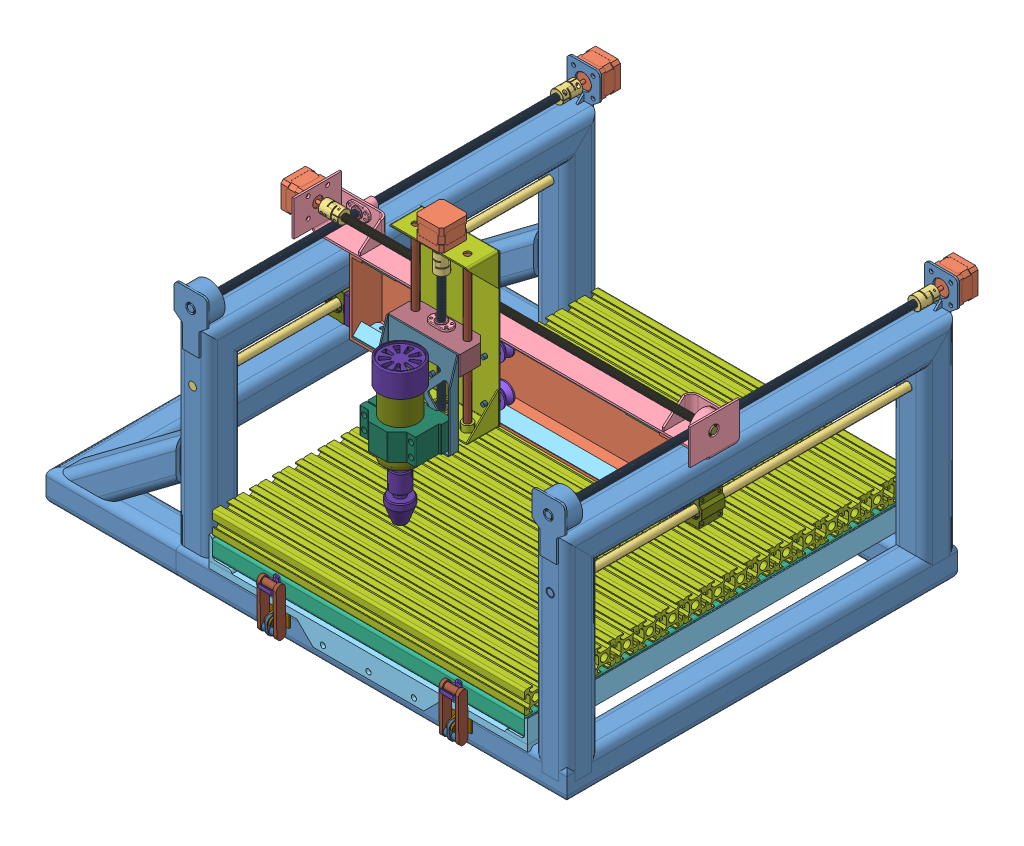
SolidWorks assembly CNC 1.0, configuration Predeterminado. Lengths in mm.
Overall size (806.85 513.22 661.72).
96 component instances, 36 part files, 133 mates.
Components (placement in the parent):
- bastidor-1: bastidor [Predeterminado<Como mecanizada>] at (-1053.2463 119.027 1114.0409) x (-1 0 0) z (0 1 0) size (800.8 613.8 400.8)
- Puente-1: Puente [Predeterminado] at (-1053.2463 333.127 1150.1798) x (0 0 1) z (-1 0 0) size (50 115 496)
- riel eje x-1: riel eje x [Predeterminado] at (-1328.2463 364.427 808.6409) x (0.953714 -0.300715 0) z (0 0 1) size (12 12 605.8)
- riel eje x-2: riel eje x [Predeterminado] at (-778.2463 364.427 805.6409) x (0.828 -0.560727 0) z (0 0 1) size (12 12 605.8)
- soporte superior puente-2: soporte superior puente [Predeterminado] at (-1053.2463 447.127 1177.1798) x (1 0 0) z (0 1 0) size (612.02 76.01 60.01)
- Riel inferior eje Y-2: Riel inferior eje Y [Predeterminado<Como mecanizada>] at (-1053.2463 352.1478 1186.0376) x (1 0 0) z (0 -0.707107 -0.707107) size (488 29.73 29.73)
- Riel superior eje Y-1: Riel superior eje Y [Predeterminado<Como mecanizada>] at (-1053.2463 433.1062 1186.0376) x (-1 0 0) z (0 0.707107 -0.707107) size (488 29.73 29.73)
- eje z-1: eje z [Predeterminado] at (-1121.4295 412.2919 938.479) x (0 0 -1) z (1 0 0) size (79 235.47 120)
  - base eje Z-1: base eje Z [Predeterminado] at (-267.5586 43.8217 -2.3467) x (0 0 -1) z (1 0 0) size (120 235.47 50)
  - Conjunto rodillo eje Y-1: Conjunto rodillo eje Y [Predeterminado] at (-239.2795 9.9817 -72.3048) x (1 0 0) z (0 0.031575 0.999501) size (36 30.93 30.93)
    - rodillo eje Y-1: rodillo eje Y [Predeterminado] at (-16.2791 0.8532 30) size (16 30 30)
    - Rodamiento 9x17-1: Rodamiento 9x17 [Predeterminado] at (-15.2791 0.8532 30) x (1 0 0) z (0 0.05029 0.998735) size (4 17 17)
    - Rodamiento 9x17-2: Rodamiento 9x17 [Predeterminado] at (-5.2791 0.8532 30) x (1 0 0) z (0 -0.414161 0.910204) size (4 17 17)
    - Eje de Rodillo en Y-2: Eje de Rodillo en Y [Predeterminado] at (-15.2791 0.8532 30) x (-1 0 0) z (0 0.999501 0.031575) size (36 30 30)
  - Conjunto rodillo eje Y-2: Conjunto rodillo eje Y [Predeterminado] at (-239.2795 9.9817 7.6952) x (1 0 0) z (0 0.031575 0.999501) size (36 30.93 30.93)
    - rodillo eje Y-1: rodillo eje Y [Predeterminado] at (-16.2791 0.8532 30) size (16 30 30)
    - Rodamiento 9x17-1: Rodamiento 9x17 [Predeterminado] at (-15.2791 0.8532 30) x (1 0 0) z (0 0.05029 0.998735) size (4 17 17)
    - Rodamiento 9x17-2: Rodamiento 9x17 [Predeterminado] at (-5.2791 0.8532 30) x (1 0 0) z (0 -0.414161 0.910204) size (4 17 17)
    - Eje de Rodillo en Y-2: Eje de Rodillo en Y [Predeterminado] at (-15.2791 0.8532 30) x (-1 0 0) z (0 0.999501 0.031575) size (36 30 30)
  - Conjunto rodillo eje Y-3: Conjunto rodillo eje Y [Predeterminado] at (-239.2795 -52.9783 7.6952) x (1 0 0) z (0 0.031575 0.999501) size (36 30.93 30.93)
    - rodillo eje Y-1: rodillo eje Y [Predeterminado] at (-16.2791 0.8532 30) size (16 30 30)
    - Rodamiento 9x17-1: Rodamiento 9x17 [Predeterminado] at (-15.2791 0.8532 30) x (1 0 0) z (0 0.05029 0.998735) size (4 17 17)
    - Rodamiento 9x17-2: Rodamiento 9x17 [Predeterminado] at (-5.2791 0.8532 30) x (1 0 0) z (0 -0.414161 0.910204) size (4 17 17)
    - Eje de Rodillo en Y-2: Eje de Rodillo en Y [Predeterminado] at (-15.2791 0.8532 30) x (-1 0 0) z (0 0.999501 0.031575) size (36 30 30)
  - Conjunto rodillo eje Y-4: Conjunto rodillo eje Y [Predeterminado] at (-239.2795 -52.9783 -72.3048) x (1 0 0) z (0 0.031575 0.999501) size (36 30.93 30.93)
    - rodillo eje Y-1: rodillo eje Y [Predeterminado] at (-16.2791 0.8532 30) size (16 30 30)
    - Rodamiento 9x17-1: Rodamiento 9x17 [Predeterminado] at (-15.2791 0.8532 30) x (1 0 0) z (0 0.05029 0.998735) size (4 17 17)
    - Rodamiento 9x17-2: Rodamiento 9x17 [Predeterminado] at (-5.2791 0.8532 30) x (1 0 0) z (0 -0.414161 0.910204) size (4 17 17)
    - Eje de Rodillo en Y-2: Eje de Rodillo en Y [Predeterminado] at (-15.2791 0.8532 30) x (-1 0 0) z (0 0.999501 0.031575) size (36 30 30)
- Guia eje z-1: Guia eje z [Predeterminado] at (-1163.7761 340.377 1236.0376) x (0 1 0) z (-0.194259 0 0.98095) size (231 10 10)
- Guia eje z-2: Guia eje z [Predeterminado] at (-1083.7761 340.377 1236.0376) x (0 1 0) z (-0.034634 0 0.9994) size (231 10 10)
- rodamiento skf 10X25-1: rodamiento skf 10X25 [Predeterminado] at (-1123.7761 344.377 1236.0376) x (1 0 0) z (0 -1 0) size (25 25 8)
- Bancada eje z-1: Bancada eje z [Predeterminado] at (-1123.7761 460.3554 1242.0376) x (1 0 0) z (0 -1 0) size (110 42 30)
- soporte spindle-1: soporte spindle [Predeterminado] at (-1123.7761 395.3554 1265.0376) size (110.01 130.01 15.01)
- soporte de fijacion spindle-1: soporte de fijacion spindle [Predeterminado] at (-1123.7761 372.3554 1299.5376) x (1 0 0) z (0 -1 0) size (91 69 40)
- case spindle-1: case spindle [Predeterminado] at (-1123.7761 368.3554 1299.5376) x (-0.921943 0 0.387327) z (0 -1 0) size (52 52 120)
- eje spindle-1: eje spindle [Predeterminado] at (-1038.5141 306.3381 1358.5305) x (-0.822349 0 -0.568984) z (0.568984 0 -0.822349) size (62 219.98 62)
- Rodamiento 10x30-1: Rodamiento 10x30 [Predeterminado] at (-778.2463 469.427 1405.4409) size (30 30 9)
- Rodamiento 10x30-2: Rodamiento 10x30 [Predeterminado] at (-1328.2463 469.427 1405.4409) size (30 30 9)
- tornillo de potencia-1: tornillo de potencia [Predeterminado] at (-1328.2463 469.427 850.4409) x (-0.050492 -0.998724 0) z (0 0 1) size (11.55 10 570.26)
- nema 17-2-1: nema 17-2 [Predeterminado] at (-1328.2463 469.427 794.1409) x (0 0 1) z (-1 0 0) size (56.5 42 42)
- CPJC20-RD-5-10-1: CPJC20-RD-5-10 [Default] at (-1328.2463 469.427 824.1409) x (0 0 1) z (0.050492 0.998724 0) size (30 20 20)
- nema 17-2-2: nema 17-2 [Predeterminado] at (-778.2463 469.427 794.1409) x (0 0 1) z (-1 0 0) size (56.5 42 42)
- tornillo de potencia-3: tornillo de potencia [Predeterminado] at (-778.2463 469.427 850.4409) x (-0.996451 -0.084175 0) z (0 0 1) size (11.55 10 570.26)
- CPJC20-RD-5-10-2: CPJC20-RD-5-10 [Default] at (-778.2463 469.427 824.4409) x (0 0 1) z (0.996451 0.084175 0) size (30 20 20)
- soporte ball screw-1: soporte ball screw [Predeterminado] at (-778.2463 469.427 1157.1798) size (35 20 29.83)
- soporte ball screw-2: soporte ball screw [Predeterminado] at (-1328.2463 469.427 1157.1798) x (-1 0 0) z (0 0 1) size (35 20 29.83)
- Base desmontable-1: Base desmontable [Predeterminado<Como mecanizada>] at (-1052.8463 149.427 1119.4409) x (1 0 0) z (0 1 0) size (490 600 70)
- Base-1: Base [Predeterminado] at (-955.1042 369.297 526.9409) size (480 65 595)
  - Marco base-1: Marco base [Predeterminado<Como mecanizada>] at (-97.7421 -184.87 595) x (1 0 0) z (0 -1 0) size (480 595 30)
  - perfil estructural aluminio base-1: perfil estructural aluminio base [Predeterminado] at (-337.7421 -167.37 875) x (0 0 -1) z (1 0 0) size (35 35 480)
  - perfil estructural aluminio base-2: perfil estructural aluminio base [Predeterminado] at (-337.7421 -167.37 840) x (0 0 -1) z (1 0 0) size (35 35 480)
  - perfil estructural aluminio base-3: perfil estructural aluminio base [Predeterminado] at (-337.7421 -167.37 805) x (0 0 -1) z (1 0 0) size (35 35 480)
  - perfil estructural aluminio base-4: perfil estructural aluminio base [Predeterminado] at (-337.7421 -167.37 770) x (0 0 -1) z (1 0 0) size (35 35 480)
  - perfil estructural aluminio base-5: perfil estructural aluminio base [Predeterminado] at (-337.7421 -167.37 735) x (0 0 -1) z (1 0 0) size (35 35 480)
  - perfil estructural aluminio base-6: perfil estructural aluminio base [Predeterminado] at (-337.7421 -167.37 700) x (0 0 -1) z (1 0 0) size (35 35 480)
  - perfil estructural aluminio base-7: perfil estructural aluminio base [Predeterminado] at (-337.7421 -167.37 665) x (0 0 -1) z (1 0 0) size (35 35 480)
  - perfil estructural aluminio base-8: perfil estructural aluminio base [Predeterminado] at (-337.7421 -167.37 630) x (0 0 -1) z (1 0 0) size (35 35 480)
  - perfil estructural aluminio base-9: perfil estructural aluminio base [Predeterminado] at (-337.7421 -167.37 595) x (0 0 -1) z (1 0 0) size (35 35 480)
  - perfil estructural aluminio base-10: perfil estructural aluminio base [Predeterminado] at (-337.7421 -167.37 560) x (0 0 -1) z (1 0 0) size (35 35 480)
  - perfil estructural aluminio base-11: perfil estructural aluminio base [Predeterminado] at (-337.7421 -167.37 525) x (0 0 -1) z (1 0 0) size (35 35 480)
  - perfil estructural aluminio base-12: perfil estructural aluminio base [Predeterminado] at (-337.7421 -167.37 490) x (0 0 -1) z (1 0 0) size (35 35 480)
  - perfil estructural aluminio base-13: perfil estructural aluminio base [Predeterminado] at (-337.7421 -167.37 455) x (0 0 -1) z (1 0 0) size (35 35 480)
  - perfil estructural aluminio base-14: perfil estructural aluminio base [Predeterminado] at (-337.7421 -167.37 420) x (0 0 -1) z (1 0 0) size (35 35 480)
  - perfil estructural aluminio base-15: perfil estructural aluminio base [Predeterminado] at (-337.7421 -167.37 385) x (0 0 -1) z (1 0 0) size (35 35 480)
  - perfil estructural aluminio base-16: perfil estructural aluminio base [Predeterminado] at (-337.7421 -167.37 350) x (0 0 -1) z (1 0 0) size (35 35 480)
  - perfil estructural aluminio base-17: perfil estructural aluminio base [Predeterminado] at (-337.7421 -167.37 315) x (0 0 -1) z (1 0 0) size (35 35 480)
- seguro-1: seguro [Predeterminado] at (-1192.8463 155.3166 1395.4799) x (0 0 1) z (-1 0 0) size (19.92 24 20)
- chumacera-1: chumacera [Predeterminado] at (-1192.8463 139.4328 1409.7811) x (0 0 1) z (-1 0 0) size (20.75 20 30)
- binario-1: binario [Predeterminado] at (-1192.8463 121.4573 1428.8384) x (0 0.100405 -0.994947) z (1 0 0) size (15 27 20)
- binario 2-1: binario 2 [Predeterminado] at (-1192.8463 145.4835 1428.7365) x (0 -0.999861 -0.016683) z (1 0 0) size (74 14 30)
- binario 2-2: binario 2 [Predeterminado] at (-912.8463 145.4679 1428.6255) x (0 -0.999982 -0.006047) z (1 0 0) size (74 14 30)
- binario-2: binario [Predeterminado] at (-912.8463 121.4477 1428.9425) x (0 0.083063 -0.996544) z (1 0 0) size (15 27 20)
- chumacera-2: chumacera [Predeterminado] at (-912.8463 139.4328 1409.7811) x (0 0 1) z (-1 0 0) size (20.75 20 30)
- seguro-2: seguro [Predeterminado] at (-912.8463 155.3166 1395.4799) x (0 0 1) z (-1 0 0) size (19.92 24 20)
- CPJC20-RD-5-10-3: CPJC20-RD-5-10 [Default] at (-1345.7463 485.5471 1193.7298) x (1 0 0) z (0 -0.917653 0.397382) size (30 20 20)
- nema 17-2-3: nema 17-2 [Predeterminado] at (-1375.7463 485.5471 1193.7298) size (56.5 42 42)
- tornillo de potencia eje y-1: tornillo de potencia eje y [Predeterminado] at (-1326.7963 485.5471 1193.7298) x (0 0.397382 0.917653) z (1 0 0) size (11.55 10 583.26)
- Soporte de tuerca eje Y-1: Soporte de tuerca eje Y [Predeterminado] at (-1123.8261 485.5471 1206.0398) x (1 0 0) z (0 0 -1) size (40 40 30)
- soporte ball screw-3: soporte ball screw [Predeterminado] at (-1103.8261 485.5471 1193.7298) x (0 1 0) z (1 0 0) size (35 20 29.83)
- Rodamiento 10x30-3: Rodamiento 10x30 [Predeterminado] at (-759.2463 485.5471 1193.7298) x (0 -1 0) z (1 0 0) size (30 30 9)
- CPJC20-RD-5-10-5: CPJC20-RD-5-10 [Default] at (-1123.7761 560.3502 1236.0376) x (0 -1 0) z (0.376149 0 -0.926559) size (30 20 20)
- nema 17-2-5: nema 17-2 [Predeterminado] at (-1123.7761 590.3502 1236.0376) x (0 -1 0) z (0 0 1) size (56.5 42 42)
- tornillo de potencia eje z-1: tornillo de potencia eje z [Predeterminado] at (-1123.7761 541.377 1236.0376) x (-0.926559 0 -0.376149) z (0 -1 0) size (11.55 10 204.95)
- soporte ball screw-4: soporte ball screw [Predeterminado] at (-1123.7761 460.3554 1236.0376) x (-1 0 0) z (0 1 0) size (35 20 29.83)
- PILLOW 12MM FINAL-1: PILLOW 12MM FINAL [Valor predeterminado] at (-1316.4326 385.877 1205.7043) x (0 0 -1) z (0 -1 0) size (36 28.21 42)
  - CLAMP-1: CLAMP [Valor predeterminado] at (13.886 -11.8235 21.4636) x (0 0 1) z (-1 0 0) size (21.2 20.68 1.18)
  - pillow 12mm M4-1: pillow 12mm M4 [Valor predeterminado] at (10.5245 -11.8137 21.45) size (36 28.21 42)
  - CLAMP-2: CLAMP [Valor predeterminado] at (44.1964 -11.8301 21.4981) x (0 0 1) z (-1 0 0) size (21.2 20.68 1.18)
- separador-1: separador [Default] at (-1314.2463 364.427 1177.1798) x (0 0 -1) z (0 -1 0) size (36 13 42)
- separador-2: separador [Default] at (-792.2463 364.427 1177.1798) x (0 0 1) z (0 -1 0) size (36 13 42)
- PILLOW 12MM FINAL-2: PILLOW 12MM FINAL [Valor predeterminado] at (-790.06 385.877 1148.6553) x (0 0 1) z (0 -1 0) size (36 28.21 42)
  - CLAMP-1: CLAMP [Valor predeterminado] at (13.886 -11.8235 21.4636) x (0 0 1) z (-1 0 0) size (21.2 20.68 1.18)
  - pillow 12mm M4-1: pillow 12mm M4 [Valor predeterminado] at (10.5245 -11.8137 21.45) size (36 28.21 42)
  - CLAMP-2: CLAMP [Valor predeterminado] at (44.1964 -11.8301 21.4981) x (0 0 1) z (-1 0 0) size (21.2 20.68 1.18)
- Pieza2^CNC 1.0-1: Pieza2^CNC 1.0 [Predeterminado] at origin size (50 39.3 36) (virtual)
Mates (geometry in assembly coordinates):
- Coincidente1: coincident aligned: plane of bastidor-1; plane of Puente-1 through (-1053.2463 333.127 1150.1798) normal (-1 0 0)
- Distancia1: distance = 60.5 mm aligned: plane of bastidor-1 through (-790.9463 393.627 1389.0409) normal (0 -1 0); plane of Puente-1 through (-805.2463 333.127 1150.1798) normal (0 -1 0)
- Distancia límite1: limit distance = 285.7389 mm anti-aligned: plane of bastidor-1 through (-790.9463 419.027 864.4409) normal (0 0 1); plane of Puente-1 through (-805.2463 333.127 1150.1798) normal (0 0 -1)
- Concéntrica1: concentric aligned: cylinder of bastidor-1 through (-1328.2463 364.427 884.2398) axis (0 0 -1) radius 6; cylinder of riel eje x-1 through (-1328.2463 364.427 1414.4409) axis (0 0 -1) radius 6
- Coincidente2: coincident aligned: plane of bastidor-1 through (-1340.9463 419.027 1414.4409) normal (0 0 1); plane of riel eje x-1 through (-1328.2463 364.427 1414.4409) normal (0 0 1)
- Concéntrica2: concentric aligned: cylinder of bastidor-1 through (-778.2463 364.427 884.2398) axis (0 0 -1) radius 6; cylinder of riel eje x-2 through (-778.2463 364.427 1411.4409) axis (0 0 -1) radius 6
- Coincidente3: coincident anti-aligned: plane of bastidor-1 through (-778.2463 364.427 1411.4409) normal (0 0 -1); plane of riel eje x-2 through (-778.2463 364.427 1411.4409) normal (0 0 1)
- Coincidente6: coincident anti-aligned: plane of Puente-1 through (-805.2463 448.127 1150.1798) normal (0 1 0); plane of soporte superior puente-2 through (-1053.2463 448.127 1177.1798) normal (0 -1 0)
- Coincidente7: coincident aligned: plane of Puente-1 through (-805.2463 337.127 1200.1798) normal (0 0 1); plane of soporte superior puente-2 through (-1353.2463 451.127 1200.1798) normal (0 0 1)
- Coincidente9: coincident anti-aligned: plane of bastidor-1; plane of soporte superior puente-2
- Coincidente11: coincident anti-aligned: plane of Puente-1 through (-805.2463 337.127 1154.1798) normal (0 1 0); plane of Riel inferior eje Y-2 through (-1053.2463 337.127 1186.0376) normal (0 -1 0)
- Coincidente12: coincident anti-aligned: plane of Puente-1 through (-1297.2463 333.127 1150.1798) normal (1 0 0); plane of Riel inferior eje Y-2 through (-1297.2463 339.127 1200.1798) normal (-1 0 0)
- Coincidente25: coincident aligned: plane of Puente-1 through (-805.2463 337.127 1200.1798) normal (0 0 1); plane of Riel inferior eje Y-2 through (-1297.2463 339.127 1200.1798) normal (0 0 1)
- Coincidente23: coincident anti-aligned: plane of soporte superior puente-2 through (-1053.2463 448.127 1177.1798) normal (0 -1 0); plane of Riel superior eje Y-1 through (-1053.2463 448.127 1186.0376) normal (0 1 0)
- Coincidente26: coincident aligned: plane of soporte superior puente-2 through (-1353.2463 451.127 1200.1798) normal (0 0 1); plane of Riel superior eje Y-1 through (-1297.2463 446.127 1200.1798) normal (0 0 1)
- Coincidente24: coincident anti-aligned: plane of Puente-1 through (-1297.2463 333.127 1150.1798) normal (1 0 0); plane of Riel superior eje Y-1 through (-1297.2463 445.127 1174.0168) normal (-1 0 0)
- Coincidente28: coincident anti-aligned: plane of Riel superior eje Y-1; plane of eje z-1/Conjunto rodillo eje Y-4
- Distancia3: distance = 7.25 mm anti-aligned: plane of eje z-1/base eje Z-1 through (-1123.7761 340.377 1206.0376) normal (0 1 0); plane of Puente-1 through (-805.2463 333.127 1150.1798) normal (0 -1 0)
- Concéntrica3: concentric aligned: cylinder of eje z-1/base eje Z-1 through (-1163.7761 561.8502 1236.0376) axis (0 1 0) radius 5; cylinder of Guia eje z-1 through (-1163.7761 340.377 1236.0376) axis (0 1 0) radius 5
- Coincidente31: coincident anti-aligned: plane of eje z-1/base eje Z-1 through (-1123.7761 340.377 1206.0376) normal (0 1 0); plane of Guia eje z-1 through (-1163.7761 340.377 1236.0376) normal (0 -1 0)
- Concéntrica4: concentric aligned: cylinder of eje z-1/base eje Z-1 through (-1083.7761 561.8502 1236.0376) axis (0 1 0) radius 5; cylinder of Guia eje z-2 through (-1083.7761 340.377 1236.0376) axis (0 1 0) radius 5
- Coincidente32: coincident anti-aligned: plane of eje z-1/base eje Z-1 through (-1123.7761 340.377 1206.0376) normal (0 1 0); plane of Guia eje z-2 through (-1083.7761 340.377 1236.0376) normal (0 -1 0)
- Distancia límite2: limit distance = 119.0702 mm anti-aligned: plane of bastidor-1 through (-1302.8463 419.027 1376.3409) normal (1 0 0); plane of eje z-1/base eje Z-1 through (-1183.7761 341.1136 1208.0376) normal (-1 0 0)
- Concéntrica5: concentric aligned: cylinder of eje z-1/base eje Z-1 through (-1123.7761 350.377 1236.0376) axis (0 -1 0) radius 12.5; cylinder of rodamiento skf 10X25-1 through (-1123.7761 348.377 1236.0376) axis (0 -1 0) radius 12.5
- Coincidente34: coincident anti-aligned: plane of eje z-1/base eje Z-1 through (-1123.7761 340.377 1206.0376) normal (0 1 0); plane of rodamiento skf 10X25-1 through (-1123.7761 340.377 1236.0376) normal (0 -1 0)
- Concéntrica6: concentric anti-aligned: cylinder of Guia eje z-1 through (-1163.7761 340.377 1236.0376) axis (0 1 0) radius 5; cylinder of Bancada eje z-1 through (-1163.7761 460.3554 1236.0376) axis (0 -1 0) radius 5
- Concéntrica7: concentric anti-aligned: cylinder of Guia eje z-2 through (-1083.7761 340.377 1236.0376) axis (0 1 0) radius 5; cylinder of Bancada eje z-1 through (-1083.7761 460.3554 1236.0376) axis (0 -1 0) radius 5
- Distancia límite3: limit distance = 79.9784 mm anti-aligned: plane of Bancada eje z-1 through (-1123.7761 430.3554 1242.0376) normal (0 -1 0); plane of eje z-1/base eje Z-1 through (-1123.7761 350.377 1206.0376) normal (0 1 0)
- Coincidente36: coincident anti-aligned: plane of Bancada eje z-1 through (-1178.7761 430.3554 1263.0376) normal (0 0 1); plane of soporte spindle-1 through (-1123.7761 395.3554 1263.0376) normal (0 0 -1)
- Coincidente37: coincident aligned: plane of Bancada eje z-1 through (-1123.7761 460.3554 1242.0376) normal (0 1 0); plane of soporte spindle-1 through (-1178.7761 460.3554 1263.0376) normal (0 1 0)
- Coincidente38: coincident aligned: plane of Bancada eje z-1 through (-1178.7761 430.3554 1221.0376) normal (-1 0 0); plane of soporte spindle-1 through (-1178.7761 395.3554 1265.0376) normal (-1 0 0)
- Coincidente39: coincident anti-aligned: plane of soporte spindle-1 through (-1123.7761 395.3554 1265.0376) normal (0 0 1); plane of soporte de fijacion spindle-1 through (-1131.7761 332.3554 1265.0376) normal (0 0 -1)
- Coincidente40: coincident aligned: plane of soporte spindle-1 through (-1123.7761 395.3554 1265.0376) normal (1 0 0); plane of soporte de fijacion spindle-1
- Coincidente41: coincident anti-aligned: plane of soporte spindle-1 through (-1123.7761 332.3554 1265.0376) normal (0 1 0); plane of soporte de fijacion spindle-1 through (-1123.7761 332.3554 1299.5376) normal (0 -1 0)
- Concéntrica8: concentric anti-aligned: cylinder of soporte de fijacion spindle-1 through (-1123.7761 332.3554 1299.5376) axis (0 1 0) radius 26; cylinder of case spindle-1 through (-1123.7761 418.3554 1299.5376) axis (0 -1 0) radius 26
- Distancia5: distance = 20 mm aligned: plane of case spindle-1 through (-1128.0367 312.3554 1289.3963) normal (0 -1 0); plane of soporte de fijacion spindle-1 through (-1123.7761 332.3554 1299.5376) normal (0 -1 0)
- Concéntrica9: concentric aligned: cylinder of case spindle-1 through (-1123.7761 368.3554 1299.5376) axis (0 -1 0) radius 6; cylinder of eje spindle-1 through (-1123.7761 245.3554 1299.5376) axis (0 -1 0) radius 6
- Distancia6: distance = 3 mm anti-aligned: plane of eje spindle-1 through (-1118.842 302.3554 1302.9515) normal (0 1 0); plane of case spindle-1 through (-1126.1001 305.3554 1294.006) normal (0 -1 0)
- Coincidente42: coincident anti-aligned: plane of bastidor-1 through (-1053.2463 119.027 1414.4409) normal (0 0 -1); plane of Rodamiento 10x30-1 through (-778.2463 469.427 1414.4409) normal (0 0 1)
- Concéntrica10: concentric anti-aligned: cylinder of bastidor-1 through (-778.2463 469.427 1389.4409) axis (0 0 1) radius 15; cylinder of Rodamiento 10x30-1 through (-778.2463 469.427 1414.4409) axis (0 0 -1) radius 15
- Coincidente43: coincident anti-aligned: plane of bastidor-1 through (-1053.2463 119.027 1414.4409) normal (0 0 -1); plane of Rodamiento 10x30-2 through (-1328.2463 469.427 1414.4409) normal (0 0 1)
- Concéntrica11: concentric anti-aligned: cylinder of bastidor-1 through (-1328.2463 469.427 1389.4409) axis (0 0 1) radius 15; cylinder of Rodamiento 10x30-2 through (-1328.2463 469.427 1414.4409) axis (0 0 -1) radius 15
- Concéntrica12: concentric aligned: cylinder of Rodamiento 10x30-2 through (-1328.2463 469.427 1414.4409) axis (0 0 -1) radius 5; cylinder of tornillo de potencia-1 through (-1328.2463 469.427 1417.4409) axis (0 0 -1) radius 5
- Coincidente44: coincident aligned: plane of bastidor-1 through (-1053.2463 119.027 1417.4409) normal (0 0 1); plane of tornillo de potencia-1 through (-1328.2463 469.427 1417.4409) normal (0 0 1)
- Concéntrica13: concentric anti-aligned: cylinder of bastidor-1 through (-1328.2463 469.427 813.6409) axis (0 0 -1) radius 12.5; cylinder of nema 17-2-1 through (-1328.2463 469.427 809.6409) axis (0 0 1) radius 11
- Paralelo1: parallel aligned: plane of bastidor-1 through (-1353.6463 119.027 813.6409) normal (-1 0 0); plane of nema 17-2-1 through (-1349.2463 448.427 810.6409) normal (-1 0 0)
- Coincidente45: coincident anti-aligned: plane of bastidor-1 through (-1053.2463 119.027 810.6409) normal (0 0 -1); plane of nema 17-2-1 through (-1328.2463 469.427 810.6409) normal (0 0 1)
- Concéntrica14: concentric anti-aligned: cylinder of nema 17-2-1 through (-1328.2463 469.427 809.6409) axis (0 0 1) radius 2.5; cylinder of CPJC20-RD-5-10-1 through (-1328.2463 469.427 834.1409) axis (0 0 -1) radius 2.5
- Coincidente46: coincident aligned: plane of nema 17-2-1 through (-1328.2463 469.427 834.1409) normal (0 0 1); circle of CPJC20-RD-5-10-1
- Coincidente47: coincident aligned: plane of tornillo de potencia-1; plane of CPJC20-RD-5-10-1
- Paralelo2: parallel anti-aligned: line of bastidor-1 through (-803.6463 454.427 810.6409) axis (0 1 0); line of nema 17-2-2 through (-799.2463 486.427 810.6409) axis (0 -1 0)
- Coincidente48: coincident anti-aligned: plane of bastidor-1 through (-1053.2463 119.027 810.6409) normal (0 0 -1); plane of nema 17-2-2 through (-778.2463 469.427 810.6409) normal (0 0 1)
- Concéntrica15: concentric anti-aligned: circle of bastidor-1; circle of nema 17-2-2
- Coincidente49: coincident aligned: plane of bastidor-1 through (-1053.2463 119.027 1417.4409) normal (0 0 1); plane of tornillo de potencia-3 through (-778.2463 469.427 1417.4409) normal (0 0 1)
- Concéntrica16: concentric aligned: circle of Rodamiento 10x30-1; circle of tornillo de potencia-3
- Concéntrica17: concentric aligned: circle of nema 17-2-2; circle of CPJC20-RD-5-10-2
- Coincidente50: coincident anti-aligned: plane of tornillo de potencia-3 through (-778.2463 469.427 850.4409) normal (0 0 -1); plane of CPJC20-RD-5-10-2 through (-778.2463 469.427 850.4409) normal (0 0 1)
- Coincidente51: coincident anti-aligned: plane of tornillo de potencia-3; plane of CPJC20-RD-5-10-2 through (-778.2463 469.427 824.4409) normal (0.996451 0.084175 0)
- Coincidente52: coincident anti-aligned: plane of soporte superior puente-2 through (-1053.2463 447.127 1157.1798) normal (0 0 1); plane of soporte ball screw-1 through (-785.7463 469.427 1157.1798) normal (0 0 -1)
- Concéntrica18: concentric aligned: cylinder of bastidor-1 through (-778.2463 469.427 813.6409) axis (0 0 -1) radius 12.5; cylinder of soporte ball screw-1 through (-778.2463 469.427 1163.1798) axis (0 0 -1) radius 8
- Tornillo1: screw = 2 mm anti-aligned: cylinder of tornillo de potencia-3 through (-778.2463 469.427 1417.4409) axis (0 0 -1) radius 5; circle of soporte ball screw-1
- Concéntrica19: concentric aligned: circle of bastidor-1; circle of soporte ball screw-2
- Coincidente53: coincident anti-aligned: plane of soporte superior puente-2 through (-1053.2463 447.127 1157.1798) normal (0 0 1); plane of soporte ball screw-2 through (-1320.7463 469.427 1157.1798) normal (0 0 -1)
- Tornillo2: screw = 1 mm anti-aligned: cylinder of tornillo de potencia-1 through (-1328.2463 469.427 1417.4409) axis (0 0 -1) radius 5; circle of soporte ball screw-2
- Paralelo3: parallel aligned: plane of soporte superior puente-2 through (-753.2463 483.127 1154.1798) normal (0 1 0); plane of soporte ball screw-1 through (-785.7463 479.427 1161.1798) normal (0 1 0)
- Paralelo4: parallel aligned: plane of soporte superior puente-2 through (-753.2463 483.127 1154.1798) normal (0 1 0); plane of soporte ball screw-2 through (-1320.7463 479.427 1161.1798) normal (0 1 0)
- Coincidente54: coincident anti-aligned: plane of bastidor-1 through (-778.2463 144.427 1401.7409) normal (0 1 0); plane of Base desmontable-1 through (-807.8463 144.427 1389.4409) normal (0 -1 0)
- Distancia7: distance = 5 mm anti-aligned: plane of bastidor-1 through (-1302.8463 119.027 851.7409) normal (1 0 0); plane of Base desmontable-1 through (-1297.8463 184.427 819.4409) normal (-1 0 0)
- Coincidente55: coincident anti-aligned: plane of Base desmontable-1 through (-812.8463 179.427 819.4409) normal (-1 0 0); plane of Base-1/Marco base-1 through (-812.8463 179.227 1419.4409) normal (1 0 0)
- Coincidente56: coincident anti-aligned: plane of Base desmontable-1 through (-1267.8463 154.427 819.4409) normal (0 1 0); plane of Base-1/Marco base-1 through (-1268.0463 154.427 824.4409) normal (0 -1 0)
- Distancia límite4: limit distance = 0 mm anti-aligned: plane of Base-1/Marco base-1 through (-812.8463 179.227 824.4409) normal (0 0 -1); plane of Base desmontable-1 through (-807.8463 159.427 824.4409) normal (0 0 1)
- Coincidente57: coincident anti-aligned: plane of bastidor-1 through (-778.2463 131.727 1414.4409) normal (0 0 1); plane of Base desmontable-1 through (-807.8463 139.427 1414.4409) normal (0 0 -1)
- Concéntrica20: concentric aligned: cylinder of binario-1 through (-1194.8463 115.4877 1428.236) axis (1 0 0) radius 4; cylinder of binario 2-1 through (-1202.8463 115.4877 1428.236) axis (1 0 0) radius 4
- Coincidente58: coincident aligned: circle of binario-1; circle of binario 2-1
- Concéntrica21: concentric anti-aligned: circle of chumacera-1; circle of binario-1
- Coincidente60: coincident anti-aligned: circle of chumacera-1; circle of binario-1
- Coincidente62: coincident anti-aligned: plane of Base-1/Marco base-1 through (-1292.8463 179.227 1419.4409) normal (0 0 1); plane of seguro-1 through (-1182.8463 159.627 1419.4409) normal (0 0 -1)
- Coincidente63: coincident anti-aligned: line of Base-1/Marco base-1 through (-1292.8463 159.627 1419.4409) axis (1 0 0); line of seguro-1 through (-1182.8463 159.627 1419.4409) axis (-1 0 0)
- Distancia8: distance = 90 mm aligned: plane of seguro-1 through (-1202.8463 175.627 1430.4409) normal (-1 0 0); plane of Base-1/Marco base-1 through (-1292.8463 179.227 824.4409) normal (-1 0 0)
- Coincidente64: coincident anti-aligned: plane of bastidor-1 through (-778.2463 131.727 1414.4409) normal (0 0 1); plane of chumacera-1 through (-1192.8463 139.4328 1414.4409) normal (0 0 -1)
- Coincidente65: coincident aligned: plane of seguro-1 through (-1192.8463 155.3166 1395.4799) normal (-1 0 0); plane of chumacera-1 through (-1192.8463 139.4328 1409.7811) normal (-1 0 0)
- Distancia9: distance = 12 mm aligned: plane of Base desmontable-1 through (-807.8463 149.427 1419.4409) normal (0 1 0); plane of chumacera-1 through (-1207.8463 137.427 1416.4409) normal (0 1 0)
- Concéntrica22: concentric aligned: cylinder of binario 2-2 through (-922.8463 115.4685 1428.4441) axis (1 0 0) radius 4; cylinder of binario-2 through (-914.8463 115.4685 1428.4441) axis (1 0 0) radius 4
- Coincidente66: coincident aligned: circle of binario 2-2; circle of binario-2
- Coincidente67: coincident anti-aligned: circle of binario-2; circle of chumacera-2
- Concéntrica23: concentric anti-aligned: circle of binario-2; circle of chumacera-2
- Coincidente68: coincident aligned: plane of chumacera-2 through (-912.8463 139.4328 1409.7811) normal (-1 0 0); plane of seguro-2 through (-912.8463 155.3166 1395.4799) normal (-1 0 0)
- Coincidente69: coincident anti-aligned: plane of Base-1/Marco base-1 through (-1292.8463 179.227 1419.4409) normal (0 0 1); plane of seguro-2 through (-902.8463 159.627 1419.4409) normal (0 0 -1)
- Distancia10: distance = 90 mm aligned: plane of Base-1/Marco base-1 through (-812.8463 179.227 1419.4409) normal (1 0 0); plane of seguro-2 through (-902.8463 175.627 1430.4409) normal (1 0 0)
- Coincidente71: coincident anti-aligned: line of Base-1/Marco base-1 through (-1292.8463 159.627 1419.4409) axis (1 0 0); line of seguro-2 through (-902.8463 159.627 1419.4409) axis (-1 0 0)
- Coincidente72: coincident anti-aligned: plane of bastidor-1 through (-778.2463 131.727 1414.4409) normal (0 0 1); plane of chumacera-2 through (-912.8463 139.4328 1414.4409) normal (0 0 -1)
- Distancia11: distance = 12 mm aligned: plane of Base desmontable-1 through (-807.8463 149.427 1419.4409) normal (0 1 0); plane of chumacera-2 through (-927.8463 137.427 1416.4409) normal (0 1 0)
- Concéntrica24: concentric anti-aligned: cylinder of CPJC20-RD-5-10-3 through (-1335.7463 485.5471 1193.7298) axis (-1 0 0) radius 2.5; cylinder of nema 17-2-3 through (-1360.2463 485.5471 1193.7298) axis (1 0 0) radius 2.5
- Coincidente73: coincident aligned: circle of CPJC20-RD-5-10-3; plane of nema 17-2-3 through (-1335.7463 485.5471 1193.7298) normal (1 0 0)
- Coincidente74: coincident anti-aligned: plane of soporte superior puente-2 through (-1359.2463 447.127 1177.1798) normal (-1 0 0); plane of nema 17-2-3 through (-1359.2463 485.5471 1193.7298) normal (1 0 0)
- Concéntrica27: concentric anti-aligned: cylinder of soporte superior puente-2 through (-747.2378 485.5471 1193.7298) axis (-1 0 0) radius 8; cylinder of nema 17-2-3 through (-1360.2463 485.5471 1193.7298) axis (1 0 0) radius 11
- Paralelo5: parallel aligned: plane of soporte superior puente-2 through (-1359.2463 508.127 1162.1798) normal (0 1 0); plane of nema 17-2-3 through (-1375.7463 506.5471 1193.7298) normal (0 1 0)
- Concéntrica28: concentric anti-aligned: circle of CPJC20-RD-5-10-3; circle of tornillo de potencia eje y-1
- Coincidente75: coincident anti-aligned: plane of CPJC20-RD-5-10-3 through (-1326.7963 474.1097 1189.1257) normal (1 0 0); plane of tornillo de potencia eje y-1 through (-1326.7963 485.5471 1193.7298) normal (-1 0 0)
- Coincidente76: coincident aligned: plane of CPJC20-RD-5-10-3 through (-1345.7463 485.5471 1193.7298) normal (0 -0.917653 0.397382); plane of tornillo de potencia eje y-1
- Concéntrica30: concentric aligned: circle of tornillo de potencia eje y-1; circle of Soporte de tuerca eje Y-1
- Paralelo6: parallel aligned: plane of eje z-1/base eje Z-1 through (-1123.7761 573.8502 1206.0376) normal (0 1 0); plane of Soporte de tuerca eje Y-1 through (-1143.8261 505.5471 1204.0398) normal (0 1 0)
- Distancia12: distance = 40 mm: line of eje z-1/base eje Z-1 through (-1183.7761 341.1136 1206.0376) axis (0 1 0); line of Soporte de tuerca eje Y-1 through (-1143.8261 465.5471 1204.0398) axis (0 1 0)
- Concéntrica31: concentric anti-aligned: circle of Soporte de tuerca eje Y-1; circle of soporte ball screw-3
- Coincidente78: coincident anti-aligned: plane of Soporte de tuerca eje Y-1 through (-1103.8261 485.5471 1206.0398) normal (1 0 0); plane of soporte ball screw-3 through (-1103.8261 478.0471 1193.7298) normal (-1 0 0)
- Paralelo7: parallel aligned: plane of Soporte de tuerca eje Y-1 through (-1103.8261 505.5471 1176.0398) normal (0 0 -1); plane of soporte ball screw-3 through (-1099.8261 478.0471 1183.7298) normal (0 0 -1)
- Tornillo3: screw = 2 mm aligned: cylinder of tornillo de potencia eje y-1 through (-746.7963 485.5471 1193.7298) axis (-1 0 0) radius 5; circle of soporte ball screw-3
- Concéntrica32: concentric anti-aligned: cylinder of soporte superior puente-2 through (-765.2463 485.5471 1193.7298) axis (1 0 0) radius 15; cylinder of Rodamiento 10x30-3 through (-750.2463 485.5471 1193.7298) axis (-1 0 0) radius 15
- Coincidente80: coincident anti-aligned: plane of soporte superior puente-2 through (-750.2463 447.127 1177.1798) normal (-1 0 0); plane of Rodamiento 10x30-3 through (-750.2463 485.5471 1193.7298) normal (1 0 0)
- Concéntrica35: concentric anti-aligned: cylinder of CPJC20-RD-5-10-5 through (-1123.7761 550.3502 1236.0376) axis (0 1 0) radius 2.5; cylinder of nema 17-2-5 through (-1123.7761 574.8502 1236.0376) axis (0 -1 0) radius 2.5
- Coincidente83: coincident aligned: circle of CPJC20-RD-5-10-5; plane of nema 17-2-5 through (-1123.7761 550.3502 1236.0376) normal (0 -1 0)
- Concéntrica36: concentric aligned: circle of eje z-1/base eje Z-1; circle of nema 17-2-5
- Coincidente84: coincident anti-aligned: plane of eje z-1/base eje Z-1 through (-1123.7761 573.8502 1206.0376) normal (0 1 0); plane of nema 17-2-5 through (-1123.7761 573.8502 1236.0376) normal (0 -1 0)
- Paralelo9: parallel aligned: plane of eje z-1/base eje Z-1 through (-1183.7761 573.8502 1256.0376) normal (0 0 1); plane of nema 17-2-5 through (-1144.7761 573.8502 1257.0376) normal (0 0 1)
- Concéntrica37: concentric anti-aligned: cylinder of rodamiento skf 10X25-1 through (-1123.7761 348.377 1236.0376) axis (0 -1 0) radius 5; cylinder of tornillo de potencia eje z-1 through (-1123.7761 338.377 1236.0376) axis (0 1 0) radius 5
- Coincidente85: coincident aligned: plane of eje z-1/base eje Z-1 through (-1123.7761 338.377 1206.0376) normal (0 -1 0); plane of tornillo de potencia eje z-1 through (-1123.7761 338.377 1236.0376) normal (0 -1 0)
- Coincidente86: coincident aligned: plane of CPJC20-RD-5-10-5 through (-1123.7761 560.3502 1236.0376) normal (0.376149 0 -0.926559); plane of tornillo de potencia eje z-1
- Concéntrica39: concentric aligned: cylinder of Bancada eje z-1 through (-1123.7761 460.3554 1236.0376) axis (0 -1 0) radius 8; cylinder of soporte ball screw-4 through (-1123.7761 466.3554 1236.0376) axis (0 -1 0) radius 8
- Coincidente87: coincident anti-aligned: plane of Bancada eje z-1 through (-1123.7761 460.3554 1242.0376) normal (0 1 0); plane of soporte ball screw-4 through (-1116.2761 460.3554 1236.0376) normal (0 -1 0)
- Paralelo10: parallel aligned: plane of soporte spindle-1 through (-1123.7761 395.3554 1265.0376) normal (0 0 1); plane of soporte ball screw-4 through (-1116.2761 464.3554 1246.0376) normal (0 0 1)
- Tornillo4: screw = 1 anti-aligned: cylinder of tornillo de potencia eje z-1 through (-1123.7761 338.377 1236.0376) axis (0 1 0) radius 5; cylinder of soporte ball screw-4 through (-1123.7761 466.3554 1236.0376) axis (0 -1 0) radius 8
- Coincidente89: coincident anti-aligned: plane of PILLOW 12MM FINAL-1/pillow 12mm M4-1 through (-1314.2463 364.427 1159.1798) normal (1 0 0); plane of separador-1 through (-1314.2463 364.427 1177.1798) normal (-1 0 0)
- Coincidente91: coincident aligned: plane of PILLOW 12MM FINAL-1/pillow 12mm M4-1 through (-1328.2463 385.427 1159.1798) normal (0 1 0); plane of separador-1 through (-1301.2463 385.427 1195.1798) normal (0 1 0)
- Coincidente92: coincident aligned: plane of PILLOW 12MM FINAL-1/pillow 12mm M4-1 through (-1328.2463 364.427 1159.1798) normal (0 0 -1); plane of separador-1 through (-1301.2463 343.427 1159.1798) normal (0 0 -1)
- Coincidente93: coincident anti-aligned: plane of Puente-1 through (-1301.2463 333.127 1150.1798) normal (-1 0 0); plane of separador-1 through (-1301.2463 364.427 1177.1798) normal (1 0 0)
- Concéntrica40: concentric aligned: cylinder of riel eje x-1 through (-1328.2463 364.427 1414.4409) axis (0 0 -1) radius 6; cylinder of PILLOW 12MM FINAL-1/pillow 12mm M4-1 through (-1328.2463 364.427 1191.8278) axis (0 0 -1) radius 6.1
- Distancia13: distance = 5 mm aligned: plane of PILLOW 12MM FINAL-1/pillow 12mm M4-1 through (-1328.2463 364.427 1195.1798) normal (0 0 1); plane of Puente-1 through (-805.2463 337.127 1200.1798) normal (0 0 1)
- Coincidente94: coincident aligned: plane of separador-2 through (-805.2463 343.427 1195.1798) normal (0 0 1); plane of PILLOW 12MM FINAL-2/pillow 12mm M4-1 through (-778.2463 364.427 1195.1798) normal (0 0 1)
- Coincidente95: coincident anti-aligned: plane of separador-2 through (-792.2463 364.427 1177.1798) normal (1 0 0); plane of PILLOW 12MM FINAL-2/pillow 12mm M4-1 through (-792.2463 364.427 1195.1798) normal (-1 0 0)
- Coincidente96: coincident aligned: plane of separador-2 through (-805.2463 385.427 1159.1798) normal (0 1 0); plane of PILLOW 12MM FINAL-2/pillow 12mm M4-1 through (-778.2463 385.427 1195.1798) normal (0 1 0)
- Coincidente97: coincident anti-aligned: plane of Puente-1 through (-805.2463 333.127 1150.1798) normal (1 0 0); plane of separador-2 through (-805.2463 364.427 1177.1798) normal (-1 0 0)
- Concéntrica41: concentric anti-aligned: cylinder of riel eje x-2 through (-778.2463 364.427 1411.4409) axis (0 0 -1) radius 6; cylinder of PILLOW 12MM FINAL-2/pillow 12mm M4-1 through (-778.2463 364.427 1162.5318) axis (0 0 1) radius 6.1
- Distancia14: distance = 5 mm aligned: plane of Puente-1 through (-805.2463 337.127 1200.1798) normal (0 0 1); plane of PILLOW 12MM FINAL-2/pillow 12mm M4-1 through (-778.2463 364.427 1195.1798) normal (0 0 1)
